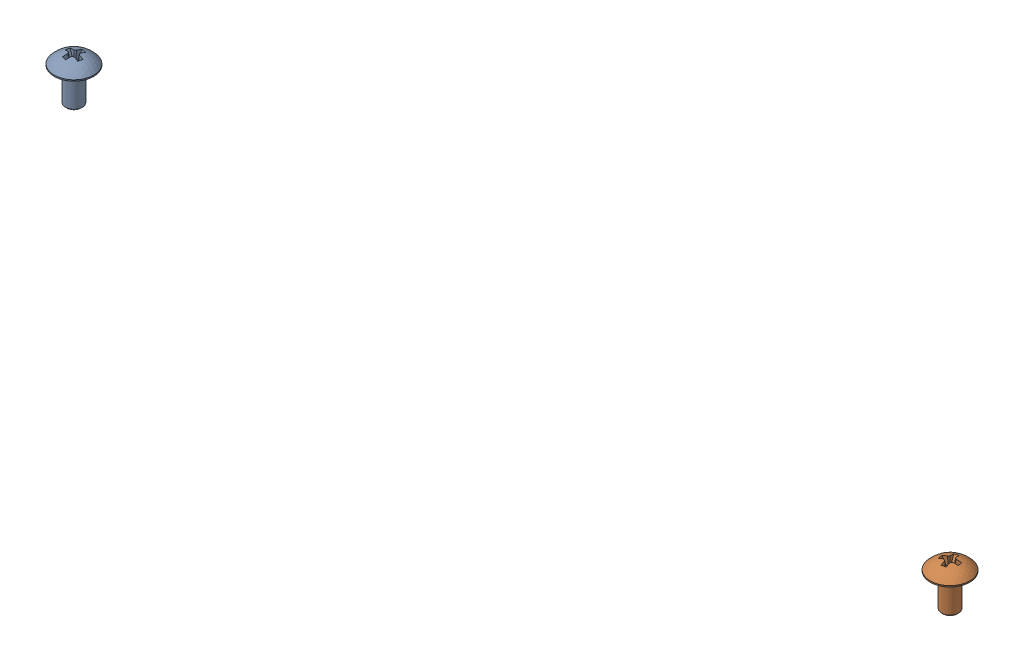
SolidWorks assembly SCREWS-025-002, configuration Default. Lengths in mm.
Overall size (219.61 10.5 11.31).
2 component instances, 1 part files, 0 mates.
Components (placement in the parent):
- SCREWS-025_default-1: SCREWS-025_default [Default] at (-104.1654 -45.9626 0) x (0 -1 0) z (-0.977968 0 -0.208756) size (10.5 9.53 9.49)
- SCREWS-025_default-2: SCREWS-025_default [Default] at (104.1654 -45.9626 0) x (0 -1 0) z (-0.977968 0 0.208756) size (10.5 9.53 9.49)
